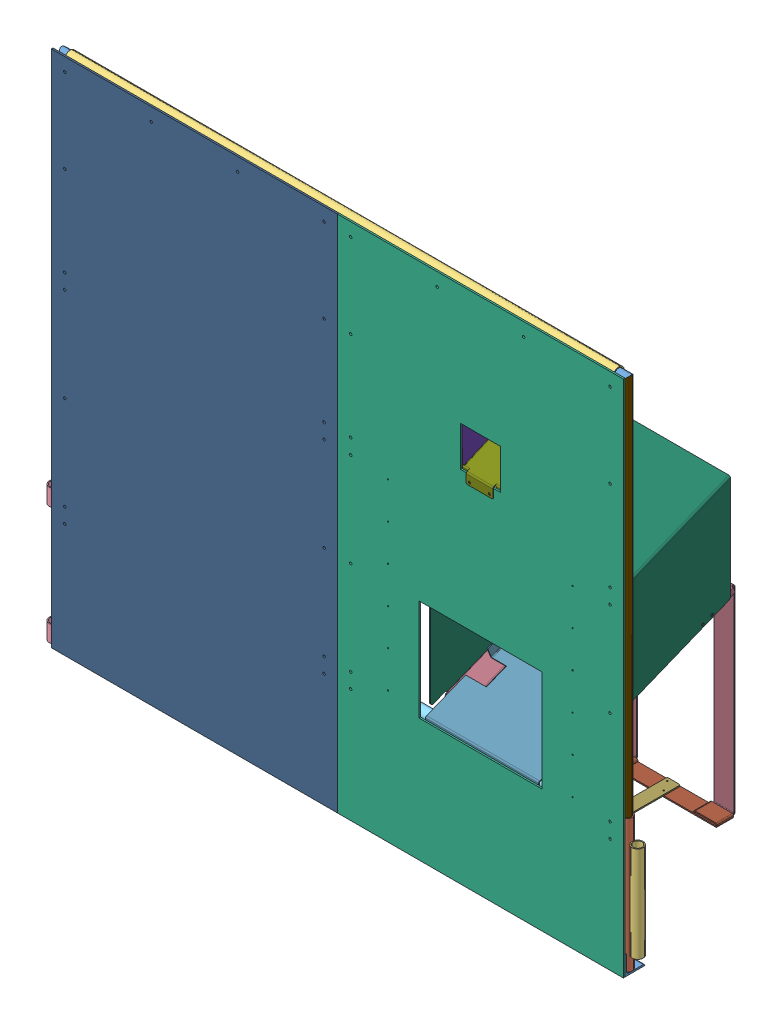
SolidWorks assembly GE-15000_ASM, configuration Default. Lengths in mm.
Overall size (2268.73 1981.2 780.07).
36 component instances, 21 part files, 0 mates.
Components (placement in the parent):
- GE-13015-R_ASM-1: GE-13015-R_ASM [Default] at origin size (2268.73 514.35 76.2)
  - GE-13015-01-1: GE-13015-01 [Default] x (1 0 0) z (0 -1 0) size (2184.4 76.2 76.2)
  - GE-13015-05-1: GE-13015-05 [Default] at (1071.118 260.35 -27.432) x (0 1 0) z (0 0 1) size (508 42.16 42.16)
  - GE-13015-05-2: GE-13015-05 [Default] at (-1071.118 260.35 -27.432) x (0 1 0) z (0 0 1) size (508 42.16 42.16)
  - GE-13015-04-1: GE-13015-04 [Default] at (1113.282 252.4125 -27.432) x (0 1 0) z (0 0 1) size (365.12 42.16 42.16)
  - GE-13015-03-1: GE-13015-03 [Default] at (-1113.282 482.6 -27.432) x (0 -1 0) z (0 0 1) size (63.5 42.16 42.16)
  - GE-13015-03-2: GE-13015-03 [Default] at (-1113.282 31.75 -27.432) x (0 -1 0) z (0 0 1) size (63.5 42.16 42.16)
  - GE-13015-02-1: GE-13015-02 [Default] at (-1071.118 463.55 -27.432) size (2143.25 42.16 42.16)
- GE-15034_ASM-1: GE-15034_ASM [Default] at (546.1 990.6 3.175) size (1092.2 1981.2 22.23)
  - GE-15003-1: GE-15003 [Default] at origin size (1092.2 1981.2 6.35)
  - GE-15037-1: GE-15037 [Default] at (352.425 -139.7 -12.7) x (-1 0 0) z (0 0 1) size (63.5 838.2 9.53)
  - GE-15037-2: GE-15037 [Default] at (-352.425 -139.7 -3.175) x (1 0 0) z (0 0 -1) size (63.5 838.2 9.53)
  - GE-15036-1: GE-15036 [Default] at (-339.725 -139.7 -19.05) size (50.8 723.9 6.35)
  - GE-15036-2: GE-15036 [Default] at (339.725 -139.7 -19.05) x (-1 0 0) z (0 0 1) size (50.8 723.9 6.35)
  - GE-15035-1: GE-15035 [Default] at (0 73.025 -6.35) x (-1 0 0) z (0 0 -1) size (676.27 412.75 6.35)
- GE-15002-1: GE-15002 [Default] at (-546.1 990.6 3.175) size (1092.2 1981.2 6.35)
- GE-15004_ASM-1: GE-15004_ASM [Default] at (546.1 4.6228 -122.9608) size (463.55 1141.84 780.07)
  - GE-15005-1: GE-15005 [Default] at origin size (457.2 14.29 63.5)
  - GE-15006-1: GE-15006 [Default] at (0 0 -288.925) size (50.8 4.62 641.35)
  - GE-15005-2: GE-15005 [Default] at (0 0 -577.85) size (457.2 14.29 63.5)
  - GE-15007-1: GE-15007 [Default] at (185.8772 0 40.9905) x (1 0 0) z (0 -1 0) size (85.44 660.4 764.01)
  - GE-15007-2: GE-15007 [Default] at (-185.8772 0 40.9905) x (1 0 0) z (0 -1 0) size (85.44 660.4 764.01)
  - GE-15008-1: GE-15008 [Default] at (0.2819 619.9194 -243.2609) x (1 0 0) z (0 -0.374607 0.927184) size (431.8 86.39 806.43)
  - GE-15009-1: GE-15009 [Default] at (-0.0025 453.7355 91.7786) x (1 0 0) z (0 -1 0) size (463.55 685.8 650.75)
- GE-15010-1: GE-15010 [Default] at (546.1 1407.001 -72.0988) x (1 0 0) z (0 -0.920505 -0.390731) size (153.12 178.41 48.41)
- GE-15011-1: GE-15011 [Default] at (546.1 1353.2065 -2.2473) x (1 0 0) z (0 -0.999848 -0.017452) size (158.75 152.4 234.67)
- GE-15012_ASM-1: GE-15012_ASM [Default] at (1071.118 6.35 -27.432) x (-1 0 0) z (0 0 -1) size (254 1968.5 33.4)
  - GE-15012-01-1: GE-15012-01 [Default] at origin size (33.4 1968.5 33.4)
  - GE-15012-02-1: GE-15012-02 [Default] at (-16.7005 1951.7995 0) size (254 33.4 33.4)
  - GE-15012-03-1: GE-15012-03 [Default] at (5.5245 1231.9 0) size (231.78 33.4 33.4)
- GE-15012_ASM-2: GE-15012_ASM [Default] at (-1071.118 6.35 -27.432) size (254 1968.5 33.4)
  - GE-15012-01-1: GE-15012-01 [Default] at origin size (33.4 1968.5 33.4)
  - GE-15012-02-1: GE-15012-02 [Default] at (-16.7005 1951.7995 0) size (254 33.4 33.4)
  - GE-15012-03-1: GE-15012-03 [Default] at (5.5245 1231.9 0) size (231.78 33.4 33.4)
- GE-15013-1: GE-15013 [Default] at (-1054.4175 1958.1495 -27.432) x (1 0 0) z (0 0 -1) size (2095.5 42.16 42.16)
- GE-15013-2: GE-15013 [Default] at (-1054.4175 1238.25 -27.432) x (1 0 0) z (0 0 -1) size (2095.5 42.16 42.16)
